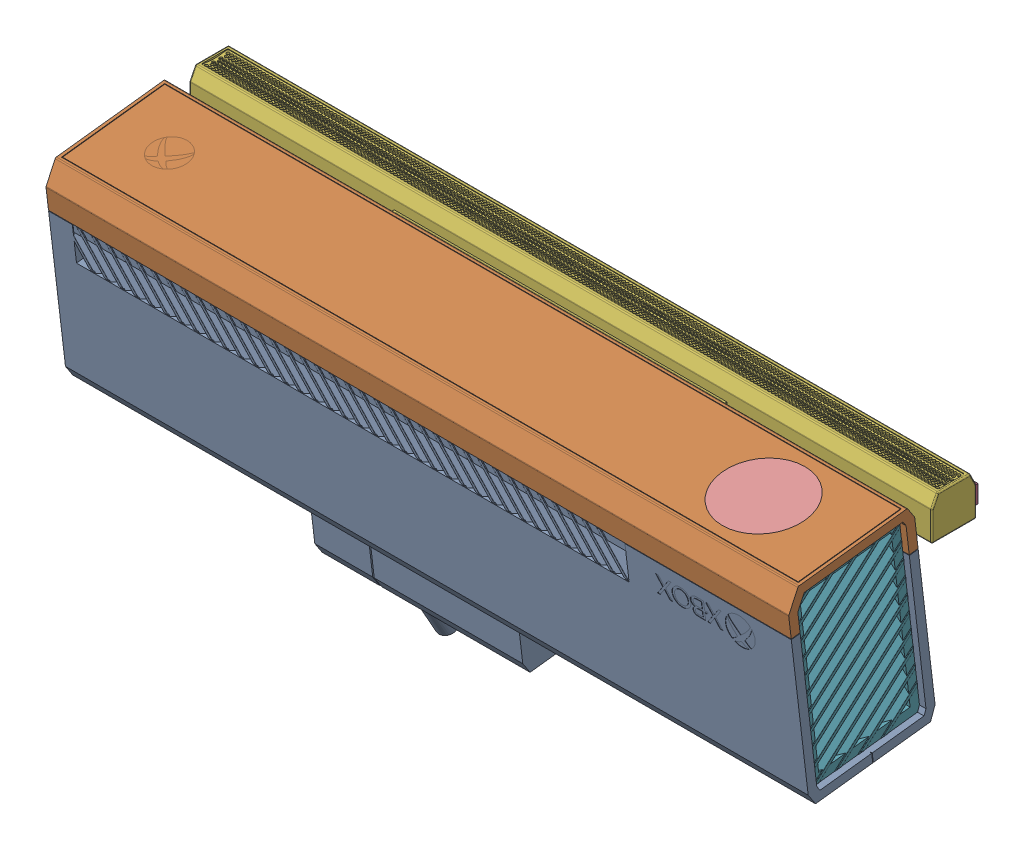
SolidWorks assembly v1AS1, configuration Default. Lengths in mm.
Overall size (250 121.83 65.49).
8 component instances, 8 part files, 19 mates.
Components (placement in the parent):
- v11-1: v11 [Default] at (-125 41.8074 21.2837) x (0 0.993094 0.117321) z (1 0 0) size (114.6 50.3 250)
- v12-1: v12 [Default] at (-125 28.1027 19.6646) x (0 0.993094 0.117321) z (1 0 0) size (13.8 43 250)
- v13-1: v13 [Default] at origin size (250 82 32.5)
- v14-1: v14 [Default] at (120 -21.7062 17.6613) x (0 0.993094 0.117321) z (1 0 0) size (60.5 37 3)
- v15-1: v15 [Default] at (-120 -21.7062 17.6613) x (0 0.993094 0.117321) z (1 0 0) size (60.5 37 3)
- v16-1: v16 [Default] at (0 -32.2685 30.3556) x (1 0 0) z (0 -0.993094 -0.117321) size (44 36 8)
- v17-1: v17 [Default] at (95 36.4213 41.3048) x (-1 0 0) z (0 0.993094 0.117321) size (28 28 3)
- v18-1: v18 [Default] at (95 31.9524 40.7769) x (-1 0 0) z (0 0.993094 0.117321) size (12 12 4)
Mates (geometry in assembly coordinates):
- Coincident3: coincident anti-aligned: plane of v11-1 through (-125.0001 29.8162 60.1452) normal (0 -0.117321 0.993094); plane of v12-1 through (125 29.8162 60.1452) normal (0 0.117321 -0.993094)
- Coincident4: coincident aligned: plane of v11-1 through (125 41.8074 21.2837) normal (1 0 0); plane of v12-1 through (125 28.1027 19.6646) normal (1 0 0)
- Coincident5: coincident aligned: plane of v11-1 through (125 41.8074 21.2837) normal (1 0 0); plane of v13-1 through (125 0 5) normal (1 0 0)
- Concentric1: concentric aligned: cylinder of v11-1 through (67 30.5 27.5) axis (-1 0 0) radius 2.5; cylinder of v13-1 through (0 30.5 27.5) axis (-1 0 0) radius 3.5
- Coincident6: coincident anti-aligned: plane of v11-1 through (120 41.8074 21.2837) normal (1 0 0); plane of v14-1 through (120 -21.7062 17.6613) normal (-1 0 0)
- Coincident8: coincident anti-aligned: plane of v11-1 through (120 36.7797 23.7106) normal (0 -0.117321 0.993094); plane of v14-1 through (122.8 27.5521 22.6205) normal (0 0.117321 -0.993094)
- Coincident9: coincident anti-aligned: plane of v11-1 through (-120 41.8074 21.2837) normal (-1 0 0); plane of v15-1 through (-120 -21.7062 17.6613) normal (1 0 0)
- Coincident10: coincident anti-aligned: plane of v11-1 through (-120 -25.8467 52.7093) normal (0 0.993094 0.117321); plane of v15-1 through (-122.8 -25.8467 52.7093) normal (0 -0.993094 -0.117321)
- Coincident11: coincident anti-aligned: plane of v11-1 through (-120 23.2112 59.3649) normal (0 0.117321 -0.993094); plane of v15-1 through (-122.8 23.2112 59.3649) normal (0 -0.117321 0.993094)
- Coincident12: coincident anti-aligned: plane of v11-1 through (-125 -30.1919 12.7779) normal (0 -0.993094 -0.117321); plane of v16-1 through (0 -32.2685 30.3556) normal (0 0.993094 0.117321)
- Coincident13: coincident anti-aligned: plane of v11-1 through (22 -30.1567 12.48) normal (-1 0 0); plane of v16-1 through (22 -38.1015 11.5414) normal (1 0 0)
- Coincident14: coincident anti-aligned: plane of v11-1 through (22 -34.3803 48.2313) normal (0 0.117321 -0.993094); plane of v16-1 through (22 -42.325 47.2928) normal (0 -0.117321 0.993094)
- Coincident16: coincident anti-aligned: plane of v11-1 through (-125.0001 38.3759 24.7592) normal (0 0.993094 0.117321); plane of v12-1 through (125 38.3759 24.7592) normal (0 -0.993094 -0.117321)
- Concentric2: concentric anti-aligned: cylinder of v12-1 through (95 25.6959 40.0378) axis (0 0.993094 0.117321) radius 14; cylinder of v17-1 through (95 39.4006 41.6568) axis (0 -0.993094 -0.117321) radius 14
- Coincident17: coincident aligned: plane of v12-1 through (125 41.5728 23.2699) normal (0 0.993094 0.117321); plane of v17-1 through (95 39.4006 41.6568) normal (0 0.993094 0.117321)
- Concentric3: concentric anti-aligned: cylinder of v11-1 through (95 31.9524 40.7769) axis (0 0.993094 0.117321) radius 6; cylinder of v18-1 through (95 33.9386 41.0115) axis (0 -0.993094 -0.117321) radius 6
- Coincident18: coincident anti-aligned: plane of v11-1 through (95 31.9524 40.7769) normal (0 0.993094 0.117321); plane of v18-1 through (95 31.9524 40.7769) normal (0 -0.993094 -0.117321)
- Coincident19: coordinate: point of v13-1; point of assembly
- Coincident20: coincident anti-aligned: plane of v12-1 through (125 38.3759 24.7592) normal (0 -0.993094 -0.117321); plane of v14-1 through (122.8 38.3759 24.7592) normal (0 0.993094 0.117321)
